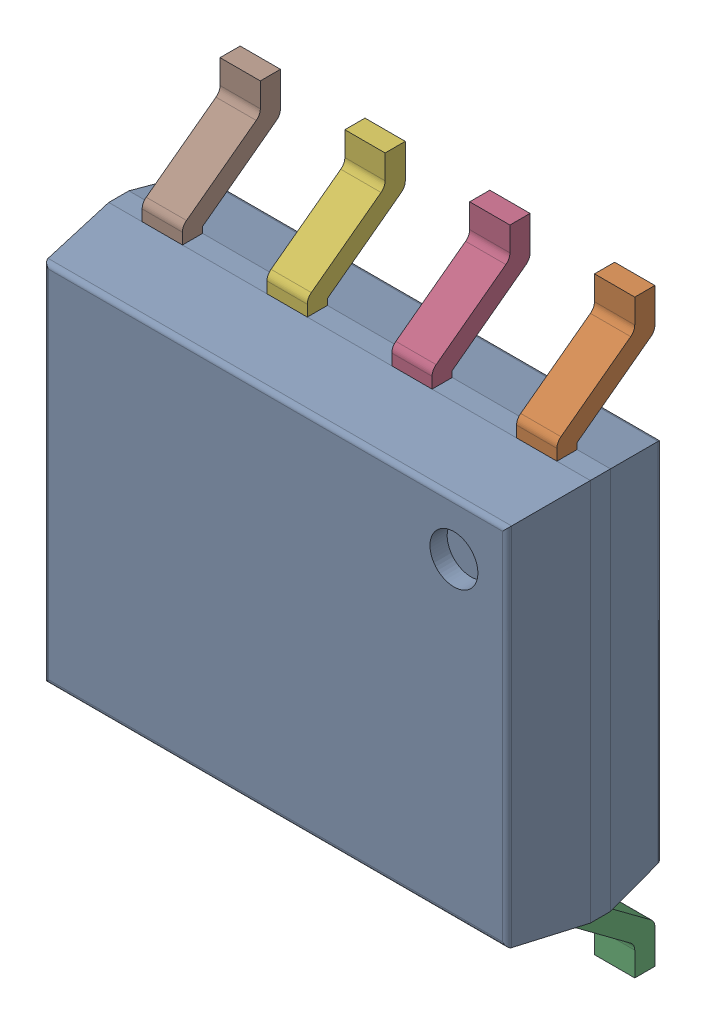
SolidWorks assembly IC8_1.step, configuration Default. Lengths in mm.
Overall size (4.9 6 1.75).
3 component instances, 2 part files, 0 mates.
Components (placement in the parent):
- 6348793408_1.step-11: 6348793408_1.step [Default] at (367.9567 250.8316 0) x (0 -1 0) z (0 0 1) size (6 4.9 1.75)
  - Body-1216_1.step-21: Body-1216_1.step [Default] at origin size (3.9 4.9 1.57)
  - PinsArrayLR-1217_1.step-21: PinsArrayLR-1217_1.step [Default] at origin size (6 4.22 1)
